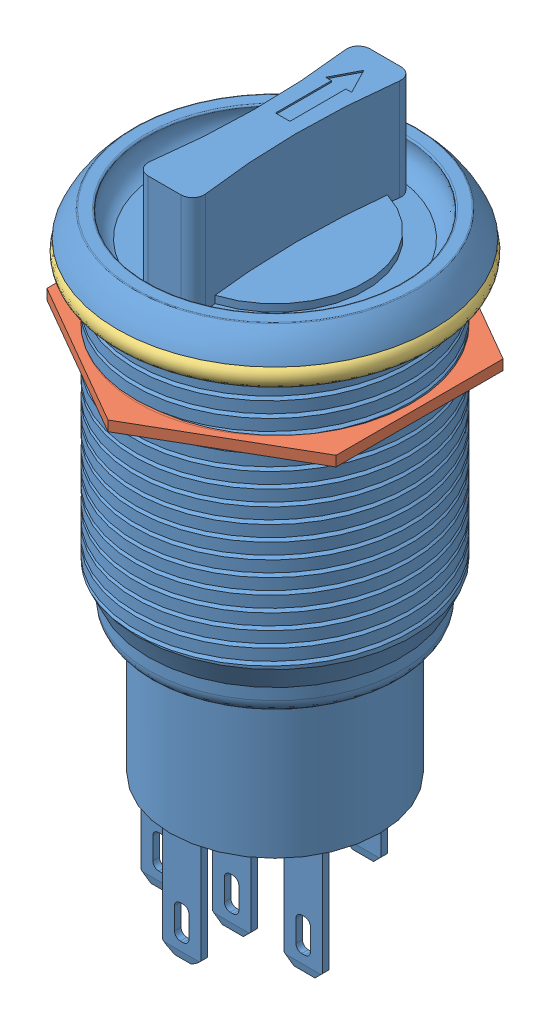
SolidWorks assembly Button_Full_Assem, configuration Default. Lengths in mm.
Overall size (26.89 47 26.89).
3 component instances, 3 part files, 4 mates.
Components (placement in the parent):
- Switch_19mm_Red-1: Switch_19mm_Red [Default] at (17.2611 45.0833 37.6387) size (21.8 47 21.8)
- rigng-1: rigng [Default] at (9.3611 39.2833 37.6387) size (20 0.71 23.09)
- Rubber_-2: Rubber_ [Default] at (9.3611 44.3333 37.6387) x (0.966788 0 -0.255579) z (0.255579 0 0.966788) size (22 1.5 22)
Mates (geometry in assembly coordinates):
- Concentric2: concentric: circle of Switch_19mm_Red-1; circle of Rubber_-2
- Tangent2: tangent: plane of Switch_19mm_Red-1 through (17.2611 45.0833 37.6387) normal (0 -1 0); torus of Rubber_-2
- Concentric3: concentric: circle of rigng-1; circle of Rubber_-2
- Distance1: distance = 5.1 mm: plane of rigng-1 through (9.3611 39.9833 37.6387) normal (0 1 0); plane of Switch_19mm_Red-1 through (17.2611 45.0833 37.6387) normal (0 -1 0)
